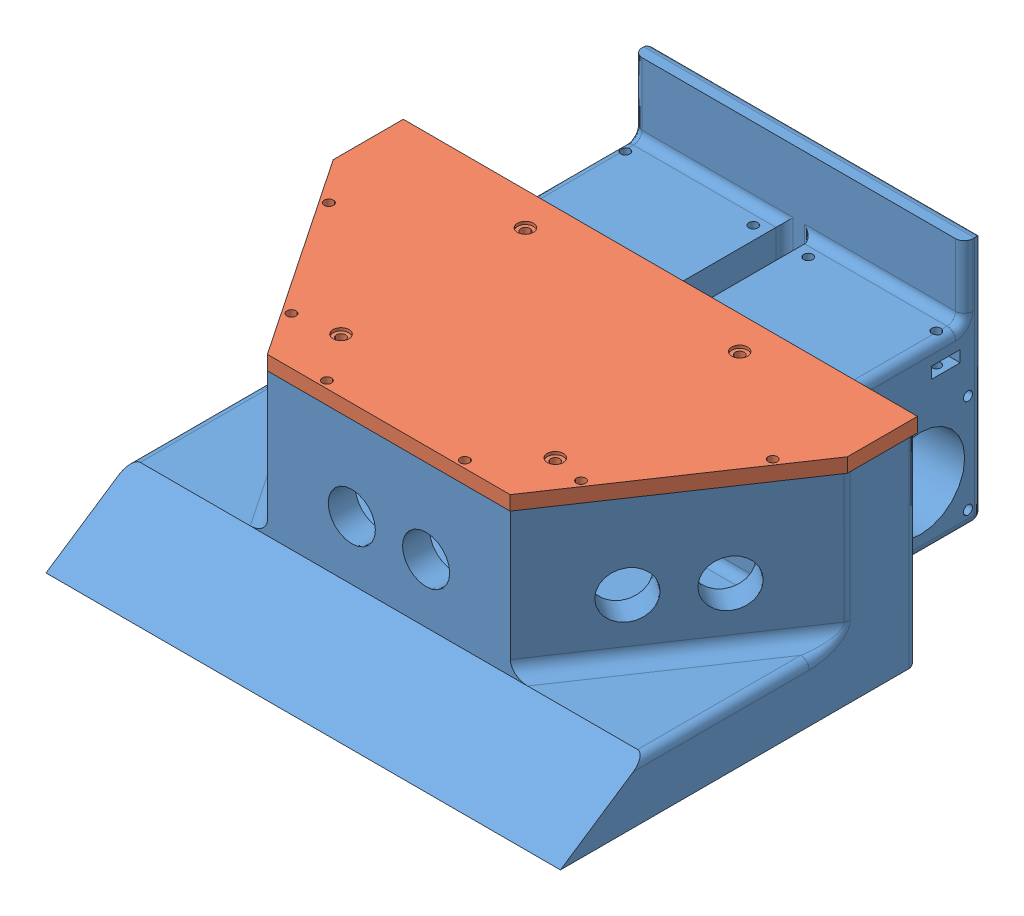
SolidWorks assembly piso placa mas sumo 5.0, configuration Default. Lengths in mm.
Overall size (180.03 105.5 185.6).
2 component instances, 2 part files, 2 mates.
Components (placement in the parent):
- Sumo 5.0-4: Sumo 5.0 [Default] at (-137.0742 17.6421 -240.4319) size (180 105.5 185.6)
- Piso para agarrar la placa del sumo 5.0-1: Piso para agarrar la placa del sumo 5.0 [Default] at (-126.2326 45.7666 -114.1054) x (1 0 0.000425) z (0.000425 0 -1) size (179.99 5 95)
Mates (geometry in assembly coordinates):
- Coincident1: coincident anti-aligned: plane of Sumo 5.0-4 through (-137.0742 40.7666 -240.4319) normal (0 1 0); plane of Piso para agarrar la placa del sumo 5.0-1 through (-126.2326 40.7666 -114.1054) normal (0 -1 0)
- Coincident2: coincident anti-aligned: circle of Sumo 5.0-4; circle of Piso para agarrar la placa del sumo 5.0-1
